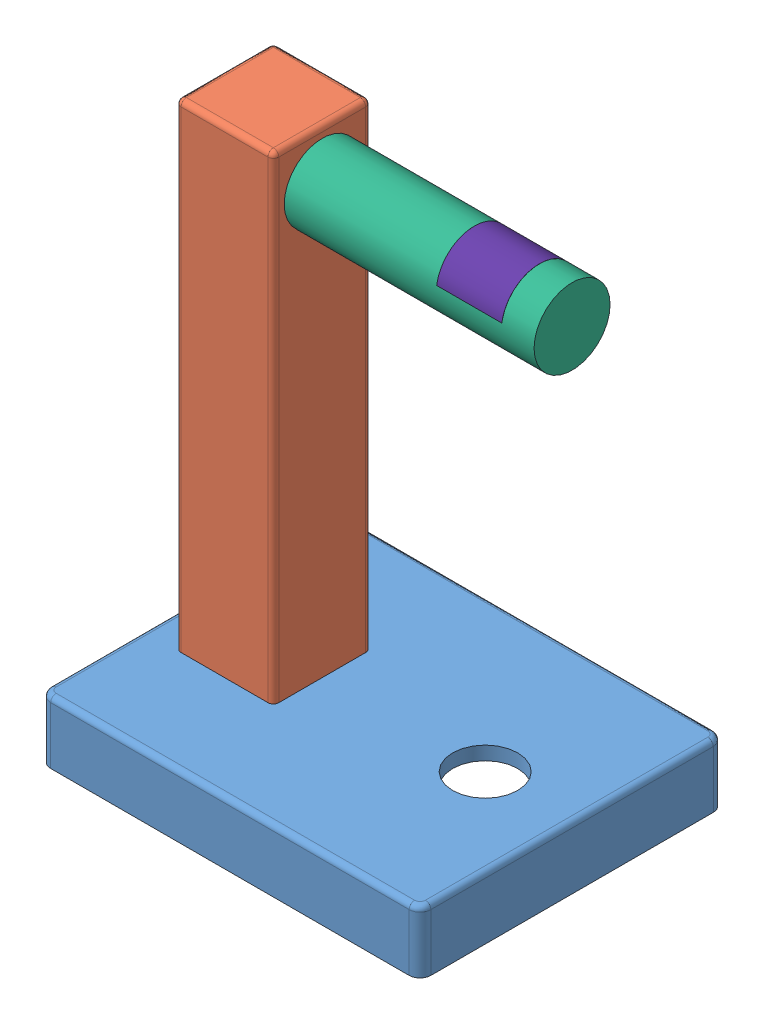
SolidWorks assembly smartstand-enclosure, configuration Default. Lengths in mm.
Overall size (227.72 315.91 177.8).
282 component instances, 47 part files, 37 mates.
Components (placement in the parent):
- smartstand-enclosure-base-1: smartstand-enclosure-base [Default] at origin size (222.25 36.51 177.8)
- smartstand-enclosure-upright-1: smartstand-enclosure-upright [Default] at (-64.5704 7.9375 1.143) x (0 0 -1) z (1 0 0) size (57.15 279.4 57.15)
- 90016A029_BRASS TAPPING INSERTS FOR HARDWOOD-1: 90016A029_BRASS TAPPING INSERTS FOR HARDWOOD [90016A029] at (-77.7875 7.9375 -14.2875) x (-1 0 0) z (0 0 1) size (11.84 13.05 11.53)
- 90016A029_BRASS TAPPING INSERTS FOR HARDWOOD-2: 90016A029_BRASS TAPPING INSERTS FOR HARDWOOD [90016A029] at (-49.2125 7.9375 14.2875) x (-1 0 0) z (0 0 1) size (11.84 13.05 11.53)
- 90016A029_BRASS TAPPING INSERTS FOR HARDWOOD-3: 90016A029_BRASS TAPPING INSERTS FOR HARDWOOD [90016A029] at (-49.2125 7.9375 -14.2875) x (-1 0 0) z (0 0 1) size (11.84 13.05 11.53)
- 90016A029_BRASS TAPPING INSERTS FOR HARDWOOD-4: 90016A029_BRASS TAPPING INSERTS FOR HARDWOOD [90016A029] at (-77.7875 7.9375 14.2875) x (-1 0 0) z (0 0 1) size (11.84 13.05 11.53)
- 92240A541_18-8 STAINLESS STEEL HEX HEAD CAP SCREW-1: 92240A541_18-8 STAINLESS STEEL HEX HEAD CAP SCREW [92240A541] at (-77.7875 7.3501 -14.2875) x (0 1 0) z (0 0 1) size (26.68 12.83 11.11)
- 92240A541_18-8 STAINLESS STEEL HEX HEAD CAP SCREW-2: 92240A541_18-8 STAINLESS STEEL HEX HEAD CAP SCREW [92240A541] at (-77.7875 7.3501 14.2875) x (0 1 0) z (0 0 1) size (26.68 12.83 11.11)
- 92240A541_18-8 STAINLESS STEEL HEX HEAD CAP SCREW-3: 92240A541_18-8 STAINLESS STEEL HEX HEAD CAP SCREW [92240A541] at (-49.2125 7.3501 14.2875) x (0 1 0) z (0 0 1) size (26.68 12.83 11.11)
- 92240A541_18-8 STAINLESS STEEL HEX HEAD CAP SCREW-4: 92240A541_18-8 STAINLESS STEEL HEX HEAD CAP SCREW [92240A541] at (-49.2125 7.3501 -14.2875) x (0 1 0) z (0 0 1) size (26.68 12.83 11.11)
- 91525A118_TYPE 316 STAINLESS STEEL FLAT WASHER-1: 91525A118_TYPE 316 STAINLESS STEEL FLAT WASHER [91525A118] at (-49.2125 -1.778 -14.2875) x (0 1 0) z (0 0 1) size (1.78 14.27 14.27)
- 91525A118_TYPE 316 STAINLESS STEEL FLAT WASHER-2: 91525A118_TYPE 316 STAINLESS STEEL FLAT WASHER [91525A118] at (-49.2125 -1.778 14.2875) x (0 1 0) z (0 0 1) size (1.78 14.27 14.27)
- 91525A118_TYPE 316 STAINLESS STEEL FLAT WASHER-3: 91525A118_TYPE 316 STAINLESS STEEL FLAT WASHER [91525A118] at (-77.7875 -1.778 -14.2875) x (0 1 0) z (0 0 1) size (1.78 14.27 14.27)
- 91525A118_TYPE 316 STAINLESS STEEL FLAT WASHER-4: 91525A118_TYPE 316 STAINLESS STEEL FLAT WASHER [91525A118] at (-77.7875 -1.778 14.2875) x (0 1 0) z (0 0 1) size (1.78 14.27 14.27)
- smartstand-enclosure-arm-1: smartstand-enclosure-arm [Default] at (111.125 258.7625 0) x (0 0 -1) z (1 0 0) size (44.45 44.45 190.5)
- smartstand-headphone-detection-rev-c-1: smartstand-headphone-detection-rev-c [Default] at (60.325 255.5875 12.7) size (26.2 3.1 25.7)
  - smartstandheadphonedetectionrevc-1: smartstandheadphonedetectionrevc [Default] at origin size (25.4 1.6 25.4)
  - C0402-1: C0402 [Default] at (13.462 1.6 -15.748) x (0 0 -1) z (0 1 0) size (1 0.5 0.5)
  - C0603-1: C0603 [Default] at (20.193 1.6 -15.875) x (-1 0 0) z (0 1 0) size (1.6 0.8 0.3)
  - C0603-2: C0603 [Default] at (19.05 1.6 -10.287) x (1 0 0) z (0 1 0) size (1.6 0.8 0.3)
  - C0603-3: C0603 [Default] at (15.113 1.6 -16.383) x (0 0 -1) z (0 1 0) size (1.6 0.8 0.3)
  - T1MSINGLE5POS_T1M5POS-1: T1MSINGLE5POS_T1M5POS [Default] at (3.048 1.6 -12.7) x (0 0 -1) z (0 1 0) size (8.03 6.25 1)
  - R0402-1: R0402 [Default] at (11.557 1.6 -16.129) x (1 0 0) z (0 1 0) size (1.01 0.5 0.32)
  - R0402-2: R0402 [Default] at (11.176 1.6 -2.286) x (0 0 1) z (0 1 0) size (1.01 0.5 0.32)
  - R0402-3: R0402 [Default] at (13.208 1.6 -5.207) x (0 0 1) z (0 1 0) size (1.01 0.5 0.32)
  - R0402-4: R0402 [Default] at (8.763 1.6 -6.096) x (0 0 -1) z (0 1 0) size (1.01 0.5 0.32)
  - R0402-5: R0402 [Default] at (6.731 1.6 -3.048) x (0 0 -1) z (0 1 0) size (1.01 0.5 0.32)
  - TESTPOINT1_5WITHGND_TESTPOINTWITHGND-1: TESTPOINT1_5WITHGND_TESTPOINTWITHGND [Default] at (12.192 1.6 -21.717) x (0 0 -1) z (0 1 0) size (4.7 2.1 1)
  - TESTPOINT1_5WITHGND_TESTPOINTWITHGND-2: TESTPOINT1_5WITHGND_TESTPOINTWITHGND [Default] at (17.145 1.6 -21.717) x (0 0 -1) z (0 1 0) size (4.7 2.1 1)
  - FIDUCIAL_1MM_FIDUCIAL1MM-1: FIDUCIAL_1MM_FIDUCIAL1MM [Default] at (22.225 1.6 -22.225) size (2.9 1 3)
  - FIDUCIAL_1MM_FIDUCIAL1MM-2: FIDUCIAL_1MM_FIDUCIAL1MM [Default] at (3.175 1.6 -3.175) size (2.9 1 3)
  - FIDUCIAL_1MM_FIDUCIAL1MM-3: FIDUCIAL_1MM_FIDUCIAL1MM [Default] at (16.637 1.6 -7.874) size (2.9 1 3)
  - VL6180X_VL6180XV0NR-1: VL6180X_VL6180XV0NR [Default] at (12.7 1.6 -12.7) size (5.59 1 3.56)
  - RPDSOG5DBV_LP5907MFX2_8-1: RPDSOG5DBV_LP5907MFX2_8 [Default] at (19.558 1.6 -13.081) x (0 0 -1) z (1 0 0) size (3.63 1 4.26)
  - sot23_4210037-1: sot23_4210037 [Default] at (10.922 1.6 -5.588) x (0 0 -1) z (0 1 0) size (3.22 3.45 1.11)
  - sot23_4210037-2: sot23_4210037 [Default] at (8.89 1.6 -2.286) x (0 0 -1) z (0 1 0) size (3.22 3.45 1.11)
- smartstand-enclosure-sensor-cover-1: smartstand-enclosure-sensor-cover [Default] at origin size (38.1 19.52 44)
- smartstand-main-board-1: smartstand-main-board [Default] at (-13.8113 -7.9375 -0.0489) x (-1 0 0) z (0 0 1) size (110.75 17.47 134.62)
  - smartstandusbdacamplifierrevb-1: smartstandusbdacamplifierrevb [Default] at origin size (93.34 1.6 134.62)
  - CHEMICON_F55_CHEMICON_F55-1: CHEMICON_F55_CHEMICON_F55 [Default] at (36.83 1.6 59.309) x (0 0 1) z (0 1 0) size (9.65 7.11 1)
  - CHEMICON_F55_CHEMICON_F55-2: CHEMICON_F55_CHEMICON_F55 [Default] at (52.578 1.6 59.309) x (0 0 1) z (0 1 0) size (9.65 7.11 1)
  - CHEMICON_F55_CHEMICON_F55-3: CHEMICON_F55_CHEMICON_F55 [Default] at (60.452 1.6 59.309) x (0 0 1) z (0 1 0) size (9.65 7.11 1)
  - CHEMICON_F55_CHEMICON_F55-4: CHEMICON_F55_CHEMICON_F55 [Default] at (28.956 1.6 59.309) x (0 0 1) z (0 1 0) size (9.65 7.11 1)
  - CHEMICON_F55_CHEMICON_F55-5: CHEMICON_F55_CHEMICON_F55 [Default] at (44.704 1.6 59.309) x (0 0 1) z (0 1 0) size (9.65 7.11 1)
  - CHEMICON_F55_CHEMICON_F55-6: CHEMICON_F55_CHEMICON_F55 [Default] at (21.082 1.6 59.309) x (0 0 1) z (0 1 0) size (9.65 7.11 1)
  - C0603-1: C0603 [Default] at (69.596 1.6 28.829) x (-1 0 0) z (0 1 0) size (1.6 0.8 0.3)
  - C0603-2: C0603 [Default] at (27.94 1.6 49.276) x (0 0 -1) z (0 1 0) size (1.6 0.8 0.3)
  - C0603-3: C0603 [Default] at (33.147 1.6 38.608) x (1 0 0) z (0 1 0) size (1.6 0.8 0.3)
  - C0603-4: C0603 [Default] at (53.848 1.6 49.276) x (0 0 -1) z (0 1 0) size (1.6 0.8 0.3)
  - C0603-5: C0603 [Default] at (45.847 1.6 39.37) x (0 0 1) z (0 1 0) size (1.6 0.8 0.3)
  - C0603-6: C0603 [Default] at (16.764 1.6 38.608) x (1 0 0) z (0 1 0) size (1.6 0.8 0.3)
  - C0603-7: C0603 [Default] at (71.247 1.6 -8.001) x (1 0 0) z (0 1 0) size (1.6 0.8 0.3)
  - C0603-8: C0603 [Default] at (71.247 1.6 -15.875) x (1 0 0) z (0 1 0) size (1.6 0.8 0.3)
  - C0603-9: C0603 [Default] at (71.12 1.6 -20.701) x (1 0 0) z (0 1 0) size (1.6 0.8 0.3)
  - C0603-10: C0603 [Default] at (71.12 1.6 -28.575) x (1 0 0) z (0 1 0) size (1.6 0.8 0.3)
  - C0603-11: C0603 [Default] at (18.034 1.6 -14.605) x (-1 0 0) z (0 1 0) size (1.6 0.8 0.3)
  - C0603-12: C0603 [Default] at (22.352 1.6 -18.034) x (0 0 1) z (0 1 0) size (1.6 0.8 0.3)
  - C0603-13: C0603 [Default] at (36.703 1.6 22.733) x (0 0 -1) z (0 1 0) size (1.6 0.8 0.3)
  - C0603-14: C0603 [Default] at (36.703 1.6 17.907) x (0 0 -1) z (0 1 0) size (1.6 0.8 0.3)
  - C0805-1: C0805 [Default] at (34.544 1.6 45.593) x (-1 0 0) z (0 1 0) size (2 1.25 0.78)
  - C0805-2: C0805 [Default] at (33.147 1.6 36.576) x (1 0 0) z (0 1 0) size (2 1.25 0.78)
  - C0805-3: C0805 [Default] at (33.147 1.6 34.036) x (1 0 0) z (0 1 0) size (2 1.25 0.78)
  - C0805-4: C0805 [Default] at (33.147 1.6 31.75) x (1 0 0) z (0 1 0) size (2 1.25 0.78)
  - C0805-5: C0805 [Default] at (33.147 1.6 29.464) x (1 0 0) z (0 1 0) size (2 1.25 0.78)
  - C0805-6: C0805 [Default] at (60.452 1.6 45.593) x (-1 0 0) z (0 1 0) size (2 1.25 0.78)
  - C0805-7: C0805 [Default] at (47.879 1.6 39.37) x (0 0 1) z (0 1 0) size (2 1.25 0.78)
  - C0805-8: C0805 [Default] at (54.991 1.6 39.37) x (0 0 1) z (0 1 0) size (2 1.25 0.78)
  - C0805-9: C0805 [Default] at (52.705 1.6 39.37) x (0 0 1) z (0 1 0) size (2 1.25 0.78)
  - C0805-10: C0805 [Default] at (50.419 1.6 39.37) x (0 0 1) z (0 1 0) size (2 1.25 0.78)
  - C0805-11: C0805 [Default] at (16.764 1.6 36.576) x (1 0 0) z (0 1 0) size (2 1.25 0.78)
  - C0805-12: C0805 [Default] at (16.764 1.6 34.036) x (1 0 0) z (0 1 0) size (2 1.25 0.78)
  - C0805-13: C0805 [Default] at (16.764 1.6 31.75) x (1 0 0) z (0 1 0) size (2 1.25 0.78)
  - C0805-14: C0805 [Default] at (16.764 1.6 29.464) x (1 0 0) z (0 1 0) size (2 1.25 0.78)
  - C0805-15: C0805 [Default] at (71.247 1.6 -10.033) x (1 0 0) z (0 1 0) size (2 1.25 0.78)
  - C0805-16: C0805 [Default] at (71.247 1.6 -13.843) x (1 0 0) z (0 1 0) size (2 1.25 0.78)
  - C0805-17: C0805 [Default] at (71.12 1.6 -22.733) x (1 0 0) z (0 1 0) size (2 1.25 0.78)
  - C0805-18: C0805 [Default] at (71.12 1.6 -26.543) x (1 0 0) z (0 1 0) size (2 1.25 0.78)
  - C0805-19: C0805 [Default] at (10.16 1.6 -16.51) x (0 0 1) z (0 1 0) size (2 1.25 0.78)
  - C0805-20: C0805 [Default] at (21.59 1.6 -14.097) x (1 0 0) z (0 1 0) size (2 1.25 0.78)
  - C0805-21: C0805 [Default] at (14.478 1.6 -14.351) x (1 0 0) z (0 1 0) size (2 1.25 0.78)
  - C0805-22: C0805 [Default] at (23.876 1.6 -22.479) x (0 0 -1) z (0 1 0) size (2 1.25 0.78)
  - C0402-1: C0402 [Default] at (27.94 1.6 30.861) x (-1 0 0) z (0 1 0) size (1 0.5 0.5)
  - C0402-2: C0402 [Default] at (29.591 1.6 49.403) x (0 0 -1) z (0 1 0) size (1 0.5 0.5)
  - C0402-3: C0402 [Default] at (33.147 1.6 40.132) x (1 0 0) z (0 1 0) size (1 0.5 0.5)
  - C0402-4: C0402 [Default] at (26.67 1.6 39.624) x (-1 0 0) z (0 1 0) size (1 0.5 0.5)
  - C0402-5: C0402 [Default] at (53.594 1.6 34.163) x (0 0 -1) z (0 1 0) size (1 0.5 0.5)
  - C0402-6: C0402 [Default] at (55.499 1.6 49.403) x (0 0 -1) z (0 1 0) size (1 0.5 0.5)
  - C0402-7: C0402 [Default] at (44.323 1.6 39.37) x (0 0 1) z (0 1 0) size (1 0.5 0.5)
  - C0402-8: C0402 [Default] at (44.831 1.6 32.893) x (0 0 -1) z (0 1 0) size (1 0.5 0.5)
  - C0402-9: C0402 [Default] at (11.557 1.6 30.861) x (-1 0 0) z (0 1 0) size (1 0.5 0.5)
  - C0402-10: C0402 [Default] at (16.764 1.6 40.132) x (1 0 0) z (0 1 0) size (1 0.5 0.5)
  - C0402-11: C0402 [Default] at (10.287 1.6 39.624) x (-1 0 0) z (0 1 0) size (1 0.5 0.5)
  - C0402-12: C0402 [Default] at (67.056 1.6 -16.256) x (-1 0 0) z (0 1 0) size (1 0.5 0.5)
  - C0402-13: C0402 [Default] at (71.247 1.6 -6.477) x (1 0 0) z (0 1 0) size (1 0.5 0.5)
  - C0402-14: C0402 [Default] at (71.247 1.6 -17.399) x (1 0 0) z (0 1 0) size (1 0.5 0.5)
  - C0402-15: C0402 [Default] at (65.278 1.6 -7.62) x (-1 0 0) z (0 1 0) size (1 0.5 0.5)
  - C0402-16: C0402 [Default] at (66.929 1.6 -28.956) x (-1 0 0) z (0 1 0) size (1 0.5 0.5)
  - C0402-17: C0402 [Default] at (71.12 1.6 -19.177) x (1 0 0) z (0 1 0) size (1 0.5 0.5)
  - C0402-18: C0402 [Default] at (71.12 1.6 -30.099) x (1 0 0) z (0 1 0) size (1 0.5 0.5)
  - C0402-19: C0402 [Default] at (65.151 1.6 -20.32) x (-1 0 0) z (0 1 0) size (1 0.5 0.5)
  - C0402-20: C0402 [Default] at (50.673 1.6 24.638) x (0 0 -1) z (0 1 0) size (1 0.5 0.5)
  - C0402-21: C0402 [Default] at (48.387 1.6 27.813) x (1 0 0) z (0 1 0) size (1 0.5 0.5)
  - C0402-22: C0402 [Default] at (22.479 1.6 3.556) x (-1 0 0) z (0 1 0) size (1 0.5 0.5)
  - C0402-23: C0402 [Default] at (32.131 1.6 12.192) x (0 0 1) z (0 1 0) size (1 0.5 0.5)
  - C0402-24: C0402 [Default] at (40.132 1.6 6.604) x (0 0 1) z (0 1 0) size (1 0.5 0.5)
  - C0402-25: C0402 [Default] at (39.751 1.6 1.778) x (1 0 0) z (0 1 0) size (1 0.5 0.5)
  - C0402-26: C0402 [Default] at (22.479 1.6 5.08) x (-1 0 0) z (0 1 0) size (1 0.5 0.5)
  - C0402-27: C0402 [Default] at (30.988 1.6 12.192) x (0 0 1) z (0 1 0) size (1 0.5 0.5)
  - C0402-28: C0402 [Default] at (32.512 1.6 -5.207) x (0 0 -1) z (0 1 0) size (1 0.5 0.5)
  - C0402-29: C0402 [Default] at (31.369 1.6 -5.207) x (0 0 -1) z (0 1 0) size (1 0.5 0.5)
  - C0402-30: C0402 [Default] at (30.226 1.6 -5.207) x (0 0 -1) z (0 1 0) size (1 0.5 0.5)
  - C0402-31: C0402 [Default] at (22.479 1.6 0.889) x (-1 0 0) z (0 1 0) size (1 0.5 0.5)
  - C0402-32: C0402 [Default] at (39.751 1.6 0.254) x (1 0 0) z (0 1 0) size (1 0.5 0.5)
  - C0402-33: C0402 [Default] at (29.083 1.6 -5.207) x (0 0 -1) z (0 1 0) size (1 0.5 0.5)
  - C0402-34: C0402 [Default] at (33.655 1.6 -5.207) x (0 0 -1) z (0 1 0) size (1 0.5 0.5)
  - C0402-35: C0402 [Default] at (22.479 1.6 2.413) x (-1 0 0) z (0 1 0) size (1 0.5 0.5)
  - C0402-36: C0402 [Default] at (41.402 1.6 6.096) x (0 0 1) z (0 1 0) size (1 0.5 0.5)
  - C0402-37: C0402 [Default] at (27.559 1.6 11.811) x (-1 0 0) z (0 1 0) size (1 0.5 0.5)
  - C0402-38: C0402 [Default] at (34.671 1.6 12.192) x (0 0 1) z (0 1 0) size (1 0.5 0.5)
  - C0402-39: C0402 [Default] at (16.51 1.6 7.62) x (-1 0 0) z (0 1 0) size (1 0.5 0.5)
  - C0402-40: C0402 [Default] at (19.685 1.6 1.143) x (0 0 -1) z (0 1 0) size (1 0.5 0.5)
  - C0402-41: C0402 [Default] at (11.938 1.6 -17.272) x (0 0 1) z (0 1 0) size (1 0.5 0.5)
  - C0402-42: C0402 [Default] at (28.448 1.6 -18.288) x (-1 0 0) z (0 1 0) size (1 0.5 0.5)
  - C0402-43: C0402 [Default] at (28.448 1.6 -21.844) x (-1 0 0) z (0 1 0) size (1 0.5 0.5)
  - C0402-44: C0402 [Default] at (22.606 1.6 -15.748) x (1 0 0) z (0 1 0) size (1 0.5 0.5)
  - C0402-45: C0402 [Default] at (11.938 1.6 -15.24) x (0 0 1) z (0 1 0) size (1 0.5 0.5)
  - C0402-46: C0402 [Default] at (22.098 1.6 -22.098) x (0 0 -1) z (0 1 0) size (1 0.5 0.5)
  - C0402-47: C0402 [Default] at (46.609 1.6 -15.113) x (-1 0 0) z (0 1 0) size (1 0.5 0.5)
  - C0402-48: C0402 [Default] at (55.245 1.6 -19.304) x (0 0 1) z (0 1 0) size (1 0.5 0.5)
  - C0402-49: C0402 [Default] at (47.752 1.6 -26.67) x (-1 0 0) z (0 1 0) size (1 0.5 0.5)
  - C0402-50: C0402 [Default] at (54.102 1.6 -22.606) x (0 0 -1) z (0 1 0) size (1 0.5 0.5)
  - C0402-51: C0402 [Default] at (52.578 1.6 -12.827) x (1 0 0) z (0 1 0) size (1 0.5 0.5)
  - C0402-52: C0402 [Default] at (52.578 1.6 -13.97) x (1 0 0) z (0 1 0) size (1 0.5 0.5)
  - C0402-53: C0402 [Default] at (52.578 1.6 -15.113) x (1 0 0) z (0 1 0) size (1 0.5 0.5)
  - C0402-54: C0402 [Default] at (45.593 1.6 -23.114) x (-1 0 0) z (0 1 0) size (1 0.5 0.5)
  - C0402-55: C0402 [Default] at (45.593 1.6 -21.971) x (-1 0 0) z (0 1 0) size (1 0.5 0.5)
  - C0402-56: C0402 [Default] at (45.593 1.6 -20.828) x (-1 0 0) z (0 1 0) size (1 0.5 0.5)
  - C0402-57: C0402 [Default] at (28.575 1.6 -65.151) x (1 0 0) z (0 1 0) size (1 0.5 0.5)
  - C0402-58: C0402 [Default] at (28.575 1.6 -64.008) x (1 0 0) z (0 1 0) size (1 0.5 0.5)
  - C0402-59: C0402 [Default] at (28.575 1.6 -62.865) x (1 0 0) z (0 1 0) size (1 0.5 0.5)
  - C0402-60: C0402 [Default] at (28.448 1.6 -51.943) x (1 0 0) z (0 1 0) size (1 0.5 0.5)
  - C0402-61: C0402 [Default] at (28.448 1.6 -50.8) x (1 0 0) z (0 1 0) size (1 0.5 0.5)
  - C0402-62: C0402 [Default] at (28.448 1.6 -49.657) x (1 0 0) z (0 1 0) size (1 0.5 0.5)
  - C0402-63: C0402 [Default] at (31.369 1.6 -50.165) x (-1 0 0) z (0 1 0) size (1 0.5 0.5)
  - C0402-64: C0402 [Default] at (31.369 1.6 -51.308) x (-1 0 0) z (0 1 0) size (1 0.5 0.5)
  - C0402-65: C0402 [Default] at (31.369 1.6 -52.451) x (-1 0 0) z (0 1 0) size (1 0.5 0.5)
  - C0402-66: C0402 [Default] at (31.242 1.6 -36.957) x (-1 0 0) z (0 1 0) size (1 0.5 0.5)
  - C0402-67: C0402 [Default] at (31.242 1.6 -38.1) x (-1 0 0) z (0 1 0) size (1 0.5 0.5)
  - C0402-68: C0402 [Default] at (31.242 1.6 -39.243) x (-1 0 0) z (0 1 0) size (1 0.5 0.5)
  - C0402-69: C0402 [Default] at (35.179 1.6 22.733) x (0 0 -1) z (0 1 0) size (1 0.5 0.5)
  - C0402-70: C0402 [Default] at (33.909 1.6 22.733) x (0 0 -1) z (0 1 0) size (1 0.5 0.5)
  - C0402-71: C0402 [Default] at (35.179 1.6 17.907) x (0 0 -1) z (0 1 0) size (1 0.5 0.5)
  - C0402-72: C0402 [Default] at (33.909 1.6 17.907) x (0 0 -1) z (0 1 0) size (1 0.5 0.5)
  - C0402-73: C0402 [Default] at (23.241 1.6 20.447) x (0 0 1) z (0 1 0) size (1 0.5 0.5)
  - C0402-74: C0402 [Default] at (21.082 1.6 -3.556) x (0 0 -1) z (0 1 0) size (1 0.5 0.5)
  - C1206-1: C1206 [Default] at (25.146 1.6 49.149) x (0 0 -1) z (0 1 0) size (3.2 1.6 1)
  - C1206-2: C1206 [Default] at (25.781 1.6 43.688) x (1 0 0) z (0 1 0) size (3.2 1.6 1)
  - C1206-3: C1206 [Default] at (51.054 1.6 49.149) x (0 0 -1) z (0 1 0) size (3.2 1.6 1)
  - C1206-4: C1206 [Default] at (51.689 1.6 43.688) x (1 0 0) z (0 1 0) size (3.2 1.6 1)
  - KEMET5MM6_07_2_KEMET5MM6_07_2-1: KEMET5MM6_07_2_KEMET5MM6_07_2 [Default] at (16.256 1.6 -54.229) x (1 0 0) z (0 1 0) size (8.89 7.62 1)
  - KEMET5MM6_07_2_KEMET5MM6_07_2-2: KEMET5MM6_07_2_KEMET5MM6_07_2 [Default] at (16.256 1.6 -46.101) x (1 0 0) z (0 1 0) size (8.89 7.62 1)
  - SOD128_5A-1: SOD128_5A [Default] at (66.675 1.6 55.88) x (0 0 -1) z (0 1 0) size (6.33 3.46 1)
  - SMA_13_6V-1: SMA_13_6V [Default] at (70.993 1.6 43.18) x (-1 0 0) z (0 1 0) size (7.1 3.5 1)
  - DIALIGHT-0603-1: DIALIGHT-0603 [Default] at (62.357 1.6 11.684) x (0 0 1) z (0 1 0) size (0.79 0.72 1.63)
  - DIALIGHT-0603-2: DIALIGHT-0603 [Default] at (68.961 1.6 11.684) x (0 0 1) z (0 1 0) size (0.79 0.72 1.63)
  - DIALIGHT-0603-3: DIALIGHT-0603 [Default] at (70.612 1.6 11.684) x (0 0 1) z (0 1 0) size (0.79 0.72 1.63)
  - DIALIGHT-0603-4: DIALIGHT-0603 [Default] at (67.31 1.6 11.684) x (0 0 1) z (0 1 0) size (0.79 0.72 1.63)
  - DIALIGHT-0603-5: DIALIGHT-0603 [Default] at (65.659 1.6 11.684) x (0 0 1) z (0 1 0) size (0.79 0.72 1.63)
  - DIALIGHT-0603-6: DIALIGHT-0603 [Default] at (64.008 1.6 11.684) x (0 0 1) z (0 1 0) size (0.79 0.72 1.63)
  - 2920L_0_6A-1: 2920L_0_6A [Default] at (69.723 1.6 48.768) x (-1 0 0) z (0 1 0) size (9.65 6.1 1)
  - PJ002A_PJ002A-1: PJ002A_PJ002A [Default] at (94.695 8.1 49.51) size (14.4 14.5 9.4)
  - 292304-1: 292304 [Default] at (94.665 7.29 21.844) x (0 0 -1) z (1 0 0) size (14.36 15.42 15.7)
  - NRJ6HH_NRJ6HH-1: NRJ6HH_NRJ6HH [Default] at (88.32 1.6 -46.61) x (0 0 -1) z (1 0 0) size (15.75 16.7 33.2)
  - PJRAN2X1U01AUX-1: PJRAN2X1U01AUX [Default] at (88.289 9.0803 -15.2344) x (0 0 -1) z (0 -1 0) size (25 19.5 17.47)
  - T1MSINGLE5POS_T1M5POS-1: T1MSINGLE5POS_T1M5POS [Default] at (50.292 1.6 12.573) x (1 0 0) z (0 1 0) size (8.03 6.25 1)
  - N2520-5002-1: N2520-5002 [Default] at (1.4342 7.3912 28.8324) x (0 1 0) z (-1 0 0) size (12.62 32.72 12.87)
  - 1X07_JP3_1X07-1: 1X07_JP3_1X07 [Default] at (3.81 1.6 -33.274) x (0 0 -1) z (1 0 0) size (17.78 1 2.62)
  - TDKVLP8040_TDKVLP8040-1: TDKVLP8040_TDKVLP8040 [Default] at (17.526 1.6 46.863) x (0 0 1) z (0 1 0) size (8.93 8.86 1)
  - TDKVLP8040_TDKVLP8040-2: TDKVLP8040_TDKVLP8040 [Default] at (43.434 1.6 46.863) x (0 0 1) z (0 1 0) size (8.93 8.86 1)
  - R0402-1: R0402 [Default] at (39.751 1.6 4.572) x (-1 0 0) z (0 1 0) size (1.01 0.5 0.32)
  - R0402-2: R0402 [Default] at (25.781 1.6 30.861) x (-1 0 0) z (0 1 0) size (1.01 0.5 0.32)
  - R0402-3: R0402 [Default] at (34.544 1.6 42.164) x (-1 0 0) z (0 1 0) size (1.01 0.5 0.32)
  - R0402-4: R0402 [Default] at (34.544 1.6 43.434) x (1 0 0) z (0 1 0) size (1.01 0.5 0.32)
  - R0402-5: R0402 [Default] at (53.594 1.6 32.004) x (0 0 -1) z (0 1 0) size (1.01 0.5 0.32)
  - R0402-6: R0402 [Default] at (60.452 1.6 42.164) x (-1 0 0) z (0 1 0) size (1.01 0.5 0.32)
  - R0402-7: R0402 [Default] at (60.452 1.6 43.434) x (1 0 0) z (0 1 0) size (1.01 0.5 0.32)
  - R0402-8: R0402 [Default] at (9.398 1.6 30.861) x (-1 0 0) z (0 1 0) size (1.01 0.5 0.32)
  - R0402-9: R0402 [Default] at (65.405 1.6 -16.637) x (0 0 -1) z (0 1 0) size (1.01 0.5 0.32)
  - R0402-10: R0402 [Default] at (63.754 1.6 -16.256) x (1 0 0) z (0 1 0) size (1.01 0.5 0.32)
  - R0402-11: R0402 [Default] at (65.278 1.6 -29.337) x (0 0 -1) z (0 1 0) size (1.01 0.5 0.32)
  - R0402-12: R0402 [Default] at (63.627 1.6 -28.956) x (1 0 0) z (0 1 0) size (1.01 0.5 0.32)
  - R0402-13: R0402 [Default] at (47.498 1.6 21.209) x (1 0 0) z (0 1 0) size (1.01 0.5 0.32)
  - R0402-14: R0402 [Default] at (20.828 1.6 1.143) x (0 0 -1) z (0 1 0) size (1.01 0.5 0.32)
  - R0402-15: R0402 [Default] at (19.685 1.6 4.318) x (1 0 0) z (0 1 0) size (1.01 0.5 0.32)
  - R0402-16: R0402 [Default] at (33.274 1.6 12.192) x (0 0 1) z (0 1 0) size (1.01 0.5 0.32)
  - R0402-17: R0402 [Default] at (51.308 1.6 17.78) x (1 0 0) z (0 1 0) size (1.01 0.5 0.32)
  - R0402-18: R0402 [Default] at (49.276 1.6 17.78) x (-1 0 0) z (0 1 0) size (1.01 0.5 0.32)
  - R0402-19: R0402 [Default] at (28.829 1.6 14.859) x (-1 0 0) z (0 1 0) size (1.01 0.5 0.32)
  - R0402-20: R0402 [Default] at (28.829 1.6 16.002) x (-1 0 0) z (0 1 0) size (1.01 0.5 0.32)
  - R0402-21: R0402 [Default] at (9.652 1.6 -21.717) x (-1 0 0) z (0 1 0) size (1.01 0.5 0.32)
  - R0402-22: R0402 [Default] at (28.448 1.6 -19.431) x (1 0 0) z (0 1 0) size (1.01 0.5 0.32)
  - R0402-23: R0402 [Default] at (28.448 1.6 -20.701) x (1 0 0) z (0 1 0) size (1.01 0.5 0.32)
  - R0402-24: R0402 [Default] at (48.26 1.6 -14.605) x (0 0 -1) z (0 1 0) size (1.01 0.5 0.32)
  - R0402-25: R0402 [Default] at (46.609 1.6 -13.843) x (1 0 0) z (0 1 0) size (1.01 0.5 0.32)
  - R0402-26: R0402 [Default] at (54.102 1.6 -19.304) x (0 0 1) z (0 1 0) size (1.01 0.5 0.32)
  - R0402-27: R0402 [Default] at (49.403 1.6 -26.035) x (0 0 1) z (0 1 0) size (1.01 0.5 0.32)
  - R0402-28: R0402 [Default] at (47.752 1.6 -25.527) x (1 0 0) z (0 1 0) size (1.01 0.5 0.32)
  - R0402-29: R0402 [Default] at (55.245 1.6 -22.606) x (0 0 -1) z (0 1 0) size (1.01 0.5 0.32)
  - R0402-30: R0402 [Default] at (49.53 1.6 -14.605) x (0 0 1) z (0 1 0) size (1.01 0.5 0.32)
  - R0402-31: R0402 [Default] at (50.8 1.6 -26.035) x (0 0 1) z (0 1 0) size (1.01 0.5 0.32)
  - R0402-32: R0402 [Default] at (26.035 1.6 -58.166) x (0 0 1) z (0 1 0) size (1.01 0.5 0.32)
  - R0402-33: R0402 [Default] at (25.908 1.6 -44.958) x (0 0 1) z (0 1 0) size (1.01 0.5 0.32)
  - R0402-34: R0402 [Default] at (28.829 1.6 22.733) x (1 0 0) z (0 1 0) size (1.01 0.5 0.32)
  - R0402-35: R0402 [Default] at (28.829 1.6 17.145) x (1 0 0) z (0 1 0) size (1.01 0.5 0.32)
  - R0402-36: R0402 [Default] at (26.162 1.6 22.733) x (-1 0 0) z (0 1 0) size (1.01 0.5 0.32)
  - R0402-37: R0402 [Default] at (20.447 1.6 -5.207) x (1 0 0) z (0 1 0) size (1.01 0.5 0.32)
  - R0402-38: R0402 [Default] at (49.276 1.6 -56.896) x (-1 0 0) z (0 1 0) size (1.01 0.5 0.32)
  - R0402-39: R0402 [Default] at (19.939 1.6 -3.556) x (0 0 1) z (0 1 0) size (1.01 0.5 0.32)
  - R0402-40: R0402 [Default] at (62.357 1.6 14.605) x (0 0 -1) z (0 1 0) size (1.01 0.5 0.32)
  - R0402-41: R0402 [Default] at (68.961 1.6 14.605) x (0 0 -1) z (0 1 0) size (1.01 0.5 0.32)
  - R0402-42: R0402 [Default] at (70.612 1.6 14.605) x (0 0 -1) z (0 1 0) size (1.01 0.5 0.32)
  - R0402-43: R0402 [Default] at (67.31 1.6 14.605) x (0 0 -1) z (0 1 0) size (1.01 0.5 0.32)
  - R0402-44: R0402 [Default] at (65.659 1.6 14.605) x (0 0 -1) z (0 1 0) size (1.01 0.5 0.32)
  - R0402-45: R0402 [Default] at (64.008 1.6 14.605) x (0 0 -1) z (0 1 0) size (1.01 0.5 0.32)
  - R1206-1: R1206 [Default] at (36.068 1.6 -56.261) x (1 0 0) z (0 1 0) size (3.1 1.55 0.55)
  - R1206-2: R1206 [Default] at (36.068 1.6 -59.055) x (1 0 0) z (0 1 0) size (3.1 1.55 0.55)
  - R1206-3: R1206 [Default] at (35.941 1.6 -43.053) x (1 0 0) z (0 1 0) size (3.1 1.55 0.55)
  - R1206-4: R1206 [Default] at (35.941 1.6 -45.847) x (1 0 0) z (0 1 0) size (3.1 1.55 0.55)
  - TQ2_TQ212V-1: TQ2_TQ212V [Default] at (36.322 1.6 -19.558) x (0 0 1) z (0 1 0) size (15.24 10.16 1)
  - TQ2_TQ212V-2: TQ2_TQ212V [Default] at (47.879 1.6 -50.927) x (-1 0 0) z (0 1 0) size (15.24 10.16 1)
  - TESTPOINT1_5WITHGND_TESTPOINTWITHGND-1: TESTPOINT1_5WITHGND_TESTPOINTWITHGND [Default] at (12.954 1.6 2.413) x (-1 0 0) z (0 1 0) size (4.7 2.1 1)
  - TESTPOINT1_5WITHGND_TESTPOINTWITHGND-2: TESTPOINT1_5WITHGND_TESTPOINTWITHGND [Default] at (58.928 1.6 -62.357) x (-1 0 0) z (0 1 0) size (4.7 2.1 1)
  - TESTPOINT1_5WITHGND_TESTPOINTWITHGND-3: TESTPOINT1_5WITHGND_TESTPOINTWITHGND [Default] at (8.509 1.6 47.117) x (0 0 -1) z (0 1 0) size (4.7 2.1 1)
  - TESTPOINT1_5WITHGND_TESTPOINTWITHGND-4: TESTPOINT1_5WITHGND_TESTPOINTWITHGND [Default] at (15.875 1.6 -2.413) x (0 0 -1) z (0 1 0) size (4.7 2.1 1)
  - TESTPOINT1_5WITHGND_TESTPOINTWITHGND-5: TESTPOINT1_5WITHGND_TESTPOINTWITHGND [Default] at (9.144 1.6 27.178) x (-1 0 0) z (0 1 0) size (4.7 2.1 1)
  - TESTPOINT1_5WITHGND_TESTPOINTWITHGND-6: TESTPOINT1_5WITHGND_TESTPOINTWITHGND [Default] at (25.527 1.6 26.67) x (-1 0 0) z (0 1 0) size (4.7 2.1 1)
  - TESTPOINT1_5WITHGND_TESTPOINTWITHGND-7: TESTPOINT1_5WITHGND_TESTPOINTWITHGND [Default] at (40.386 1.6 30.734) x (0 0 -1) z (0 1 0) size (4.7 2.1 1)
  - TESTPOINT1_5WITHGND_TESTPOINTWITHGND-8: TESTPOINT1_5WITHGND_TESTPOINTWITHGND [Default] at (59.055 1.6 35.052) x (0 0 -1) z (0 1 0) size (4.7 2.1 1)
  - TESTPOINT1_5WITHGND_TESTPOINTWITHGND-9: TESTPOINT1_5WITHGND_TESTPOINTWITHGND [Default] at (22.606 1.6 -36.195) x (-1 0 0) z (0 1 0) size (4.7 2.1 1)
  - TESTPOINT1_5WITHGND_TESTPOINTWITHGND-10: TESTPOINT1_5WITHGND_TESTPOINTWITHGND [Default] at (62.23 1.6 -36.83) x (-1 0 0) z (0 1 0) size (4.7 2.1 1)
  - FIDUCIAL_1MM_FIDUCIAL1MM-1: FIDUCIAL_1MM_FIDUCIAL1MM [Default] at (12.319 1.6 -64.262) size (2.9 1 3)
  - FIDUCIAL_1MM_FIDUCIAL1MM-2: FIDUCIAL_1MM_FIDUCIAL1MM [Default] at (54.991 1.6 -6.985) size (2.9 1 3)
  - FIDUCIAL_1MM_FIDUCIAL1MM-3: FIDUCIAL_1MM_FIDUCIAL1MM [Default] at (40.386 1.6 -5.334) size (2.9 1 3)
  - FIDUCIAL_1MM_FIDUCIAL1MM-4: FIDUCIAL_1MM_FIDUCIAL1MM [Default] at (11.176 1.6 57.15) size (2.9 1 3)
  - FIDUCIAL_1MM_FIDUCIAL1MM-5: FIDUCIAL_1MM_FIDUCIAL1MM [Default] at (79.756 1.6 -6.604) size (2.9 1 3)
  - FIDUCIAL_1MM_FIDUCIAL1MM-6: FIDUCIAL_1MM_FIDUCIAL1MM [Default] at (63.881 1.6 40.767) size (2.9 1 3)
  - FIDUCIAL_1MM_FIDUCIAL1MM-7: FIDUCIAL_1MM_FIDUCIAL1MM [Default] at (19.939 1.6 15.24) size (2.9 1 3)
  - FIDUCIAL_1MM_FIDUCIAL1MM-8: FIDUCIAL_1MM_FIDUCIAL1MM [Default] at (55.88 1.6 27.559) size (2.9 1 3)
  - TQFP64EXPOSEDPAD_XUF208256TQ64-1: TQFP64EXPOSEDPAD_XUF208256TQ64 [Default] at (31.115 1.6 3.556) x (1 0 0) z (0 1 0) size (15 15 1)
  - RPUSONN10_TPD4E02B04DQA-1: RPUSONN10_TPD4E02B04DQA [Default] at (70.104 1.6 31.369) x (0 0 -1) z (0 1 0) size (3.3 2.03 1)
  - RPDSOG6DBV_TS5A3159DBV-1: RPDSOG6DBV_TS5A3159DBV [Default] at (33.782 1.6 49.022) x (0 0 1) z (0 1 0) size (4.13 5.06 1)
  - RPDSOG6DBV_TS5A3159DBV-2: RPDSOG6DBV_TS5A3159DBV [Default] at (59.69 1.6 49.022) x (0 0 1) z (0 1 0) size (4.13 5.06 1)
  - SPVQFNN20_TPS7A3301RGW-1: SPVQFNN20_TPS7A3301RGW [Default] at (27.178 1.6 35.306) x (-1 0 0) z (0 1 0) size (7.11 7.11 1)
  - SPVQFNN20_TPS7A3301RGW-2: SPVQFNN20_TPS7A3301RGW [Default] at (49.149 1.6 33.401) x (0 0 -1) z (0 1 0) size (7.11 7.11 1)
  - SPVQFNN20_TPS7A3301RGW-3: SPVQFNN20_TPS7A3301RGW [Default] at (10.795 1.6 35.306) x (-1 0 0) z (0 1 0) size (7.11 7.11 1)
  - SPVQFNN20_TPS7A3301RGW-4: SPVQFNN20_TPS7A3301RGW [Default] at (65.151 1.6 -11.938) x (-1 0 0) z (0 1 0) size (7.11 7.11 1)
  - SPVQFNN20_TPS7A3301RGW-5: SPVQFNN20_TPS7A3301RGW [Default] at (65.024 1.6 -24.638) x (-1 0 0) z (0 1 0) size (7.11 7.11 1)
  - RPDSOG6DBV_TS5A3159DBV-3: RPDSOG6DBV_TS5A3159DBV [Default] at (47.879 1.6 24.511) x (1 0 0) z (0 1 0) size (4.13 5.06 1)
  - RPDSOG20_PCM5102A-1: RPDSOG20_PCM5102A [Default] at (17.018 1.6 -19.431) x (0 0 -1) z (0 1 0) size (7.62 8.64 1)
  - SOT457_SZNUD3124-1: SOT457_SZNUD3124 [Default] at (44.831 1.6 -38.1) x (-1 0 0) z (0 1 0) size (3.41 3.62 1)
  - DMP8_NJM4556AM-1: DMP8_NJM4556AM [Default] at (50.165 1.6 -20.32) x (-1 0 0) z (0 1 0) size (6.35 8.89 1)
  - DMP8_NJM4556AM-2: DMP8_NJM4556AM [Default] at (29.972 1.6 -57.658) x (1 0 0) z (0 1 0) size (6.35 8.89 1)
  - DMP8_NJM4556AM-3: DMP8_NJM4556AM [Default] at (29.845 1.6 -44.45) x (1 0 0) z (0 1 0) size (6.35 8.89 1)
  - RPDSOG6DBV_TS5A3159DBV-4: RPDSOG6DBV_TS5A3159DBV [Default] at (27.051 1.6 19.939) x (0 0 -1) z (0 1 0) size (4.13 5.06 1)
  - RPDSOG8DCU_SN74LVC3G34DCU-1: RPDSOG8DCU_SN74LVC3G34DCU [Default] at (59.944 1.6 13.208) x (1 0 0) z (0 1 0) size (2.54 4.57 1)
  - RPDSOG3_TPD2E007DCK-1: RPDSOG3_TPD2E007DCK [Default] at (58.674 1.6 -50.8) x (0 0 1) z (0 1 0) size (2.61 3.25 1)
  - RPDSOG3_TPD2E007DCK-2: RPDSOG3_TPD2E007DCK [Default] at (77.597 1.6 -33.528) x (0 0 1) z (0 1 0) size (2.61 3.25 1)
  - KC2520C_24_576MHZ-1: KC2520C_24_576MHZ [Default] at (16.51 1.6 5.334) x (1 0 0) z (0 1 0) size (4.06 3.05 1)
  - KC2520C_24_576MHZ-2: KC2520C_24_576MHZ [Default] at (31.623 1.6 22.733) x (0 0 -1) z (0 1 0) size (4.06 3.05 1)
  - KC2520C_24_576MHZ-3: KC2520C_24_576MHZ [Default] at (31.623 1.6 18.034) x (0 0 -1) z (0 1 0) size (4.06 3.05 1)
- 93090A250_PRESS-FIT FEMALE ROUND STANDOFFS-1: 93090A250_PRESS-FIT FEMALE ROUND STANDOFFS [93090A250] at (-100.8063 -1.5875 61.5461) x (0 -1 0) z (0 0 1) size (13 7.33 6.35)
- 93090A250_PRESS-FIT FEMALE ROUND STANDOFFS-2: 93090A250_PRESS-FIT FEMALE ROUND STANDOFFS [93090A250] at (-100.8063 -1.5875 -33.7039) x (0 -1 0) z (0 0 1) size (13 7.33 6.35)
- 93090A250_PRESS-FIT FEMALE ROUND STANDOFFS-3: 93090A250_PRESS-FIT FEMALE ROUND STANDOFFS [93090A250] at (-20.1612 -1.5875 61.5461) x (0 -1 0) z (0 0 1) size (13 7.33 6.35)
- 93090A250_PRESS-FIT FEMALE ROUND STANDOFFS-4: 93090A250_PRESS-FIT FEMALE ROUND STANDOFFS [93090A250] at (-100.8063 -1.5875 -61.6439) x (0 -1 0) z (0 0 1) size (13 7.33 6.35)
- 93090A250_PRESS-FIT FEMALE ROUND STANDOFFS-5: 93090A250_PRESS-FIT FEMALE ROUND STANDOFFS [93090A250] at (-20.1612 -1.5875 -61.6439) x (0 -1 0) z (0 0 1) size (13 7.33 6.35)
- 93090A250_PRESS-FIT FEMALE ROUND STANDOFFS-6: 93090A250_PRESS-FIT FEMALE ROUND STANDOFFS [93090A250] at (-100.8063 -1.5875 33.6061) x (0 -1 0) z (0.546944 0 -0.837169) size (13 7.33 6.35)
- 92949A144_18-8 SS BUTTON-HEAD SOCKET CAP SCREW-1: 92949A144_18-8 SS BUTTON-HEAD SOCKET CAP SCREW [92949A144] at (-100.8063 -11.3917 -61.6439) x (0.837169 0 0.546944) z (0 -1 0) size (6.65 6.65 8.58)
- 92949A144_18-8 SS BUTTON-HEAD SOCKET CAP SCREW-2: 92949A144_18-8 SS BUTTON-HEAD SOCKET CAP SCREW [92949A144] at (-100.8063 -11.3917 -33.7039) x (1 0 0) z (0 -1 0) size (6.65 6.65 8.58)
- 92949A144_18-8 SS BUTTON-HEAD SOCKET CAP SCREW-3: 92949A144_18-8 SS BUTTON-HEAD SOCKET CAP SCREW [92949A144] at (-100.8063 -11.3917 33.6061) x (1 0 0) z (0 -1 0) size (6.65 6.65 8.58)
- 92949A144_18-8 SS BUTTON-HEAD SOCKET CAP SCREW-4: 92949A144_18-8 SS BUTTON-HEAD SOCKET CAP SCREW [92949A144] at (-100.8063 -11.3917 61.5461) x (1 0 0) z (0 -1 0) size (6.65 6.65 8.58)
- 92949A144_18-8 SS BUTTON-HEAD SOCKET CAP SCREW-5: 92949A144_18-8 SS BUTTON-HEAD SOCKET CAP SCREW [92949A144] at (-20.1612 -11.3917 61.5461) x (1 0 0) z (0 -1 0) size (6.65 6.65 8.58)
- 92949A144_18-8 SS BUTTON-HEAD SOCKET CAP SCREW-6: 92949A144_18-8 SS BUTTON-HEAD SOCKET CAP SCREW [92949A144] at (-20.1612 -11.3917 -61.6439) x (1 0 0) z (0 -1 0) size (6.65 6.65 8.58)
Mates (geometry in assembly coordinates):
- Coincident2: coincident anti-aligned: plane of smartstand-enclosure-base-1 through (-104.775 7.9375 82.55) normal (0 1 0); plane of smartstand-enclosure-upright-1 through (-88.9 7.9375 25.4) normal (0 -1 0)
- Concentric2: concentric aligned: circle of smartstand-enclosure-base-1; circle of smartstand-enclosure-upright-1
- Concentric3: concentric aligned: circle of smartstand-enclosure-base-1; circle of smartstand-enclosure-upright-1
- Concentric4: concentric anti-aligned: circle of 90016A029_BRASS TAPPING INSERTS FOR HARDWOOD-1; circle of smartstand-enclosure-upright-1
- Coincident3: coincident aligned: plane of smartstand-enclosure-upright-1 through (-88.9 7.9375 25.4) normal (0 -1 0); plane of 90016A029_BRASS TAPPING INSERTS FOR HARDWOOD-1 through (-77.7875 7.9375 -14.2875) normal (0 -1 0)
- Concentric5: concentric anti-aligned: circle of smartstand-enclosure-upright-1; circle of 90016A029_BRASS TAPPING INSERTS FOR HARDWOOD-4
- Coincident4: coincident aligned: plane of smartstand-enclosure-upright-1 through (-88.9 7.9375 25.4) normal (0 -1 0); plane of 90016A029_BRASS TAPPING INSERTS FOR HARDWOOD-4 through (-77.7875 7.9375 14.2875) normal (0 -1 0)
- Concentric6: concentric anti-aligned: circle of smartstand-enclosure-upright-1; circle of 90016A029_BRASS TAPPING INSERTS FOR HARDWOOD-2
- Coincident5: coincident aligned: plane of smartstand-enclosure-upright-1 through (-88.9 7.9375 25.4) normal (0 -1 0); plane of 90016A029_BRASS TAPPING INSERTS FOR HARDWOOD-2 through (-49.2125 7.9375 14.2875) normal (0 -1 0)
- Concentric7: concentric anti-aligned: circle of smartstand-enclosure-upright-1; circle of 90016A029_BRASS TAPPING INSERTS FOR HARDWOOD-3
- Coincident6: coincident aligned: plane of smartstand-enclosure-upright-1 through (-88.9 7.9375 25.4) normal (0 -1 0); plane of 90016A029_BRASS TAPPING INSERTS FOR HARDWOOD-3 through (-49.2125 7.9375 -14.2875) normal (0 -1 0)
- ProfileCenter2: profile center = 0 mm aligned: circle of 91525A118_TYPE 316 STAINLESS STEEL FLAT WASHER-2; circle of smartstand-enclosure-base-1
- ProfileCenter3: profile center = 0 mm aligned: circle of 91525A118_TYPE 316 STAINLESS STEEL FLAT WASHER-1; circle of smartstand-enclosure-base-1
- ProfileCenter4: profile center = 0 mm aligned: circle of 91525A118_TYPE 316 STAINLESS STEEL FLAT WASHER-4; circle of smartstand-enclosure-base-1
- ProfileCenter5: profile center = 0 mm aligned: circle of 91525A118_TYPE 316 STAINLESS STEEL FLAT WASHER-3; circle of smartstand-enclosure-base-1
- ProfileCenter6: profile center = 0 mm aligned: plane of 92240A541_18-8 STAINLESS STEEL HEX HEAD CAP SCREW-1 through (-80.9954 -1.778 -8.7312) normal (0 1 0); circle of 91525A118_TYPE 316 STAINLESS STEEL FLAT WASHER-3
- ProfileCenter7: profile center = 0 mm aligned: plane of 92240A541_18-8 STAINLESS STEEL HEX HEAD CAP SCREW-2 through (-80.9954 -1.778 19.8438) normal (0 1 0); plane of 91525A118_TYPE 316 STAINLESS STEEL FLAT WASHER-4 through (-77.7875 -1.778 14.2875) normal (0 -1 0)
- ProfileCenter8: profile center = 0.0305 mm aligned: plane of 92240A541_18-8 STAINLESS STEEL HEX HEAD CAP SCREW-3 through (-52.4204 -1.778 19.8438) normal (0 1 0); plane of 91525A118_TYPE 316 STAINLESS STEEL FLAT WASHER-2 through (-49.2125 -1.778 14.2875) normal (0 -1 0)
- ProfileCenter9: profile center = 0 mm aligned: plane of 92240A541_18-8 STAINLESS STEEL HEX HEAD CAP SCREW-4 through (-52.4204 -1.778 -8.7312) normal (0 1 0); plane of 91525A118_TYPE 316 STAINLESS STEEL FLAT WASHER-1 through (-49.2125 -1.778 -14.2875) normal (0 -1 0)
- ProfileCenter10: profile center = 0 mm aligned: plane of smartstand-enclosure-upright-1 through (-79.375 258.7625 0) normal (1 0 0); plane of smartstand-enclosure-arm-1 through (-79.375 258.7625 0) normal (-1 0 0)
- Parallel1: parallel aligned: plane of smartstand-enclosure-base-1 through (-104.775 7.9375 82.55) normal (0 1 0); plane of smartstand-enclosure-arm-1 through (111.125 255.5875 0) normal (0 1 0)
- ProfileCenter11: profile center = 0 mm aligned: circle of smartstand-enclosure-arm-1; circle of smartstand-headphone-detection-rev-c-1/smartstandheadphonedetectionrevc-1
- Concentric8: concentric aligned: circle of smartstand-enclosure-arm-1; circle of smartstand-headphone-detection-rev-c-1/smartstandheadphonedetectionrevc-1
- ProfileCenter12: profile center = 0 mm aligned: circle of 93090A250_PRESS-FIT FEMALE ROUND STANDOFFS-5; plane of smartstand-enclosure-base-1 through (-20.1612 4.7625 -61.6439) normal (0 -1 0)
- ProfileCenter13: profile center = 0 mm aligned: circle of 93090A250_PRESS-FIT FEMALE ROUND STANDOFFS-3; plane of smartstand-enclosure-base-1 through (-20.1612 4.7625 61.5461) normal (0 -1 0)
- ProfileCenter14: profile center = 0 mm aligned: circle of 93090A250_PRESS-FIT FEMALE ROUND STANDOFFS-1; plane of smartstand-enclosure-base-1 through (-100.8063 4.7625 61.5461) normal (0 -1 0)
- ProfileCenter15: profile center = 0 mm aligned: plane of smartstand-enclosure-base-1 through (-100.8063 4.7625 33.6061) normal (0 -1 0); circle of 93090A250_PRESS-FIT FEMALE ROUND STANDOFFS-6
- ProfileCenter16: profile center = 0 mm aligned: circle of 93090A250_PRESS-FIT FEMALE ROUND STANDOFFS-2; plane of smartstand-enclosure-base-1 through (-100.8063 4.7625 -33.7039) normal (0 -1 0)
- ProfileCenter17: profile center = 0 mm aligned: plane of smartstand-enclosure-base-1 through (-100.8063 4.7625 -61.6439) normal (0 -1 0); circle of 93090A250_PRESS-FIT FEMALE ROUND STANDOFFS-4
- ProfileCenter18: profile center = 0 mm anti-aligned: circle of 93090A250_PRESS-FIT FEMALE ROUND STANDOFFS-3; circle of smartstand-main-board-1/smartstandusbdacamplifierrevb-1
- Concentric9: concentric anti-aligned: circle of smartstand-main-board-1/smartstandusbdacamplifierrevb-1; circle of 93090A250_PRESS-FIT FEMALE ROUND STANDOFFS-4
- ProfileCenter19: profile center = 0 mm aligned: plane of 92949A144_18-8 SS BUTTON-HEAD SOCKET CAP SCREW-4 through (-100.8063 -9.5375 58.2187) normal (0 1 0); circle of smartstand-main-board-1/smartstandusbdacamplifierrevb-1
- ProfileCenter20: profile center = 0 mm aligned: plane of 92949A144_18-8 SS BUTTON-HEAD SOCKET CAP SCREW-3 through (-100.8063 -9.5375 30.2787) normal (0 1 0); circle of smartstand-main-board-1/smartstandusbdacamplifierrevb-1
- ProfileCenter21: profile center = 0 mm aligned: plane of 92949A144_18-8 SS BUTTON-HEAD SOCKET CAP SCREW-2 through (-100.8063 -9.5375 -37.0313) normal (0 1 0); circle of smartstand-main-board-1/smartstandusbdacamplifierrevb-1
- ProfileCenter22: profile center = 0 mm aligned: circle of smartstand-main-board-1/smartstandusbdacamplifierrevb-1; plane of 92949A144_18-8 SS BUTTON-HEAD SOCKET CAP SCREW-1 through (-98.9863 -9.5375 -64.4295) normal (0 1 0)
- ProfileCenter23: profile center = 0 mm aligned: plane of 92949A144_18-8 SS BUTTON-HEAD SOCKET CAP SCREW-5 through (-20.1612 -9.5375 58.2187) normal (0 1 0); circle of smartstand-main-board-1/smartstandusbdacamplifierrevb-1
- ProfileCenter24: profile center = 0 mm aligned: circle of smartstand-main-board-1/smartstandusbdacamplifierrevb-1; plane of 92949A144_18-8 SS BUTTON-HEAD SOCKET CAP SCREW-6 through (-20.1612 -9.5375 -64.9713) normal (0 1 0)
